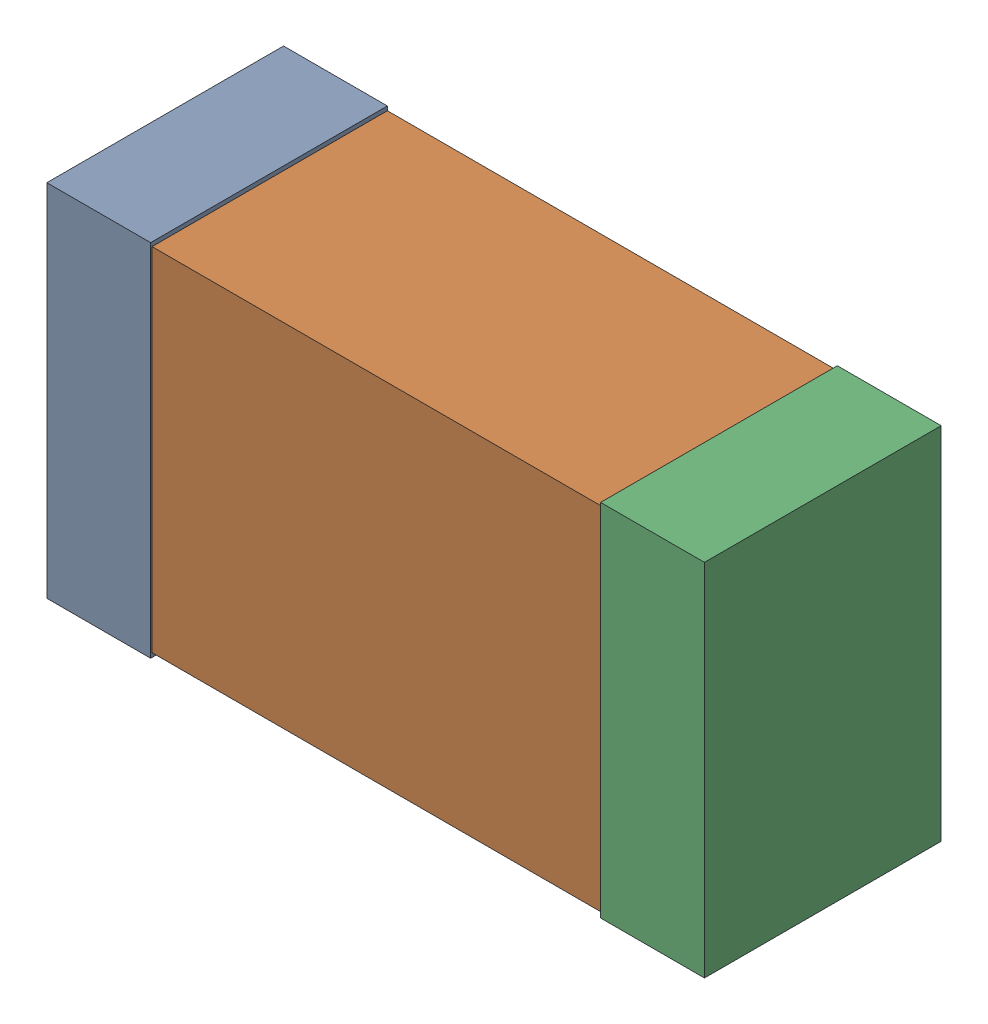
SolidWorks assembly C14_0Kanaloa_v2.0.0_Motor, configuration Default. Lengths in mm.
Overall size (2.38 1.3 0.85).
6 component instances, 2 part files, 0 mates.
Components (placement in the parent):
- 352877648-1: 352877648 [Default] at (34.052 55.88 0) size (0.38 1.3 0.85)
  - Extruded_14-1: Extruded_14 [Default] at origin size (0.38 1.3 0.85)
- 352877392-1: 352877392 [Default] at (35.052 55.88 0) size (2.2 1.27 0.85)
  - Extruded_15-1: Extruded_15 [Default] at origin size (2.2 1.27 0.85)
- 352877648-2: 352877648 [Default] at (36.052 55.88 0) size (0.38 1.3 0.85)
  - Extruded_14-1: Extruded_14 [Default] at origin size (0.38 1.3 0.85)
